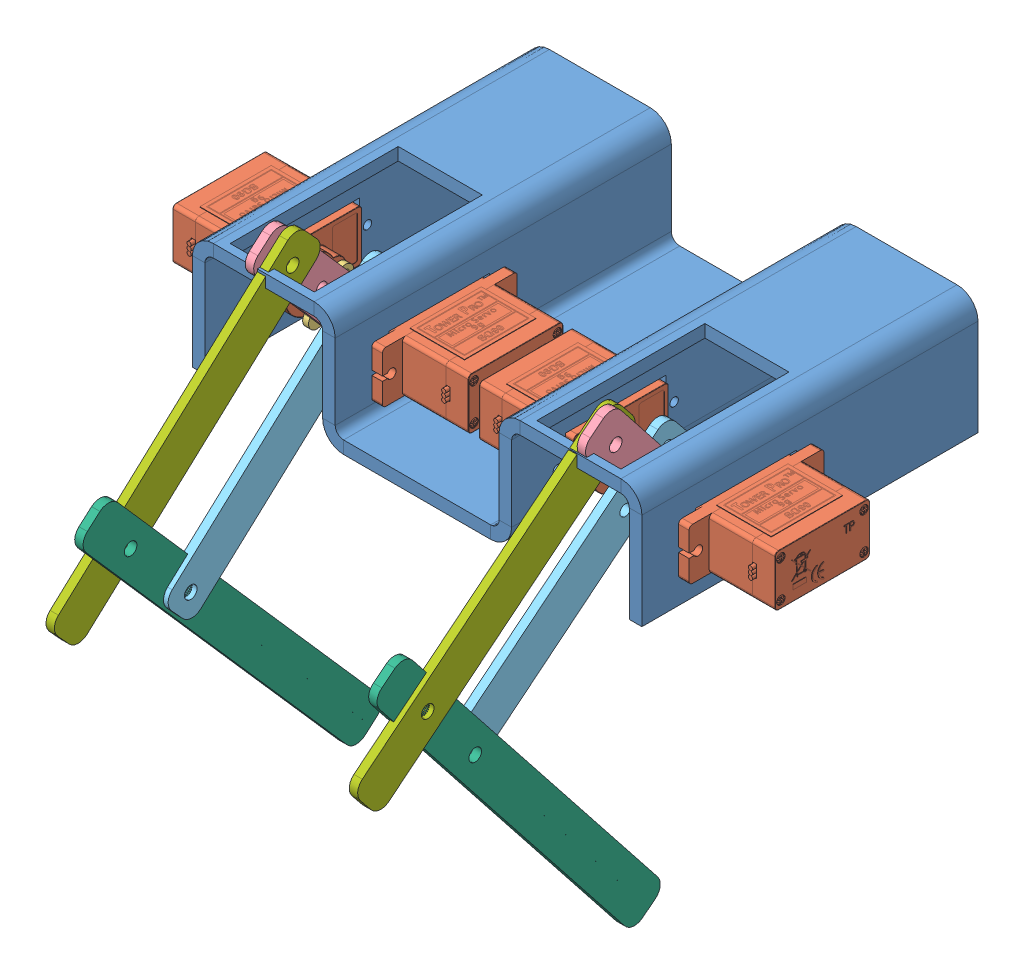
SolidWorks assembly assembly of duck round 2, configuration Default. Lengths in mm.
Overall size (143.6 114.97 133.43).
17 component instances, 7 part files, 41 mates.
Components (placement in the parent):
- body round 2-1: body round 2 [Default] at (-22.1996 -72.5458 50.5255) size (107 28 80)
- SG90 - Micro Servo 9g - Tower Pro.1-1: SG90 - Micro Servo 9g - Tower Pro.1 [Peça] at (-83.3496 -0.75 25.7508) x (0 0 -1) z (0 -1 0) size (32.1 29.95 12.4)
- SG90 - Micro Servo 9g - Tower Pro.1-2: SG90 - Micro Servo 9g - Tower Pro.1 [Peça] at (-34.0496 -0.75 25.7508) x (0 0 -1) z (0 1 0) size (32.1 29.95 12.4)
- SG90 - Micro Servo 9g - Tower Pro.1-3: SG90 - Micro Servo 9g - Tower Pro.1 [Peça] at (-10.3496 -0.75 25.7508) x (0 0 -1) z (0 -1 0) size (32.1 29.95 12.4)
- SG90 - Micro Servo 9g - Tower Pro.1-4: SG90 - Micro Servo 9g - Tower Pro.1 [Peça] at (38.9504 -0.75 25.7508) x (0 0 -1) z (0 1 0) size (32.1 29.95 12.4)
- SG90 - Micro Servo 9g - Tower Pro.4-1: SG90 - Micro Servo 9g - Tower Pro.4 [Peça] at (-55.1496 -0.75 30.9008) x (0 0.737502 0.675345) z (0 -0.675345 0.737502) size (13 3.8 16.7)
- SG90 - Micro Servo 9g - Tower Pro.4-2: SG90 - Micro Servo 9g - Tower Pro.4 [Peça] at (-62.2496 -0.75 30.9008) x (0 0.660205 -0.751086) z (0 -0.751086 -0.660205) size (13 3.8 16.7)
- SG90 - Micro Servo 9g - Tower Pro.4-3: SG90 - Micro Servo 9g - Tower Pro.4 [Peça] at (17.8504 -0.75 30.9008) x (0 -0.620104 0.78452) z (0 -0.78452 -0.620104) size (13 3.8 16.7)
- SG90 - Micro Servo 9g - Tower Pro.4-4: SG90 - Micro Servo 9g - Tower Pro.4 [Peça] at (10.7504 -0.75 30.9008) x (0 0.777148 0.629318) z (0 0.629318 -0.777148) size (13 3.8 16.7)
- arm for servo1-1: arm for servo1 [Default] at (-60.2496 4.6728 35.6674) x (0 -0.751086 -0.660205) z (0 0.660205 -0.751086) size (40 2 10)
- arm for servo2-1: arm for servo2 [Default] at (-57.1496 -17.2378 48.9061) x (0 0.675345 -0.737502) z (0 -0.737502 -0.675345) size (70 2 10)
- arm for servo3-1: arm for servo3 [Default] at (-56.2496 -50.4142 60.4581) x (0 0.751086 0.660205) z (0 -0.660205 0.751086) size (100 2 10)
- arm for servo4-1: arm for servo4 [Default] at (-58.2496 -8.69 69.1799) x (0 0.675345 -0.737502) z (0 0.737502 0.675345) size (80 2 10)
- arm for servo1-2: arm for servo1 [Default] at (15.8504 4.9142 35.3779) x (0 -0.78452 -0.620104) z (0 -0.620104 0.78452) size (40 2 10)
- arm for servo2-3: arm for servo2 [Default] at (10.7504 -16.1141 49.874) x (0 0.629318 -0.777148) z (0 -0.777148 -0.629318) size (70 2 10)
- arm for servo4-2: arm for servo4 [Default] at (13.8504 -6.4564 69.7259) x (0 0.629318 -0.777148) z (0 -0.777148 -0.629318) size (80 2 10)
- arm for servo3-2: arm for servo3 [Default] at (14.7504 -48.44 63.3071) x (0 0.78452 0.620104) z (0 -0.620104 0.78452) size (100 2 10)
Mates (geometry in assembly coordinates):
- Coincident5: coincident: plane of body round 2-1 through (-41.6996 -12.25 -29.4745) normal (1 0 0); plane of SG90 - Micro Servo 9g - Tower Pro.1-2 through (-41.6996 4.5 40.9508) normal (-1 0 0)
- Coincident7: coincident: plane of body round 2-1 through (-2.6996 -12.25 -29.4745) normal (-1 0 0); plane of SG90 - Micro Servo 9g - Tower Pro.1-3 through (-2.6996 -6 40.9508) normal (1 0 0)
- Concentric15: concentric: cylinder of SG90 - Micro Servo 9g - Tower Pro.1-3 through (-20.8996 -0.75 39.6508) axis (1 0 0) radius 1.1; cylinder of body round 2-1 through (31.3004 -0.75 39.6508) axis (-1 0 0) radius 1
- Coincident10: coincident: plane of body round 2-1 through (31.3004 12.75 -29.4745) normal (1 0 0); plane of SG90 - Micro Servo 9g - Tower Pro.1-4 through (31.3004 4.5 40.9508) normal (-1 0 0)
- Concentric17: concentric: cylinder of body round 2-1 through (31.3004 -0.75 39.6508) axis (-1 0 0) radius 1; cylinder of SG90 - Micro Servo 9g - Tower Pro.1-4 through (49.5004 -0.75 39.6508) axis (-1 0 0) radius 1.1
- Coincident13: coincident: plane of SG90 - Micro Servo 9g - Tower Pro.1-2 through (-53.3496 -0.75 30.9008) normal (-1 0 0); plane of SG90 - Micro Servo 9g - Tower Pro.4-1 through (-53.3496 -0.75 30.9008) normal (1 0 0)
- Concentric1: concentric: circle of SG90 - Micro Servo 9g - Tower Pro.1-2; circle of SG90 - Micro Servo 9g - Tower Pro.4-1
- Coincident14: coincident: plane of SG90 - Micro Servo 9g - Tower Pro.1-1 through (-64.0496 -0.75 30.9008) normal (1 0 0); plane of SG90 - Micro Servo 9g - Tower Pro.4-2 through (-64.0496 -0.75 30.9008) normal (-1 0 0)
- Concentric2: concentric: circle of SG90 - Micro Servo 9g - Tower Pro.1-1; circle of SG90 - Micro Servo 9g - Tower Pro.4-2
- Coincident15: coincident: plane of SG90 - Micro Servo 9g - Tower Pro.1-4 through (19.6504 -0.75 30.9008) normal (-1 0 0); plane of SG90 - Micro Servo 9g - Tower Pro.4-3 through (19.6504 -0.75 30.9008) normal (1 0 0)
- Concentric3: concentric: circle of SG90 - Micro Servo 9g - Tower Pro.1-4; circle of SG90 - Micro Servo 9g - Tower Pro.4-3
- Concentric4: concentric: circle of SG90 - Micro Servo 9g - Tower Pro.1-3; circle of SG90 - Micro Servo 9g - Tower Pro.4-4
- Coincident16: coincident: plane of SG90 - Micro Servo 9g - Tower Pro.1-3 through (8.9504 -0.75 30.9008) normal (1 0 0); plane of SG90 - Micro Servo 9g - Tower Pro.4-4 through (8.9504 -0.75 30.9008) normal (-1 0 0)
- Concentric16: concentric: cylinder of SG90 - Micro Servo 9g - Tower Pro.1-3 through (-20.8996 -0.75 11.8508) axis (1 0 0) radius 1.1; cylinder of body round 2-1 through (31.3004 -0.75 11.8508) axis (-1 0 0) radius 1
- Concentric18: concentric: cylinder of body round 2-1 through (31.3004 -0.75 11.8508) axis (-1 0 0) radius 1; cylinder of SG90 - Micro Servo 9g - Tower Pro.1-4 through (49.5004 -0.75 11.8508) axis (-1 0 0) radius 1.1
- Concentric19: concentric: cylinder of SG90 - Micro Servo 9g - Tower Pro.4-2 through (-62.2496 4.0945 35.1591) axis (1 0 0) radius 1.25; cylinder of arm for servo1-1 through (-59.2496 4.0945 35.1591) axis (-1 0 0) radius 1.3
- Concentric20: concentric: cylinder of SG90 - Micro Servo 9g - Tower Pro.4-2 through (-62.2496 -5.5945 26.6424) axis (1 0 0) radius 1.25; cylinder of arm for servo1-1 through (-59.2496 -5.5945 26.6424) axis (-1 0 0) radius 1.3
- Coincident19: coincident: plane of SG90 - Micro Servo 9g - Tower Pro.4-2 through (-62.2496 -0.75 30.9008) normal (1 0 0); plane of arm for servo1-1 through (-62.2496 4.6728 35.6674) normal (-1 0 0)
- Concentric21: concentric: cylinder of SG90 - Micro Servo 9g - Tower Pro.4-1 through (-55.1496 3.606 26.1439) axis (-1 0 0) radius 1.25; cylinder of arm for servo2-1 through (-58.1496 3.606 26.1439) axis (1 0 0) radius 1.3
- Concentric22: concentric: cylinder of arm for servo2-1 through (-58.1496 -5.106 35.6577) axis (1 0 0) radius 1.3; cylinder of SG90 - Micro Servo 9g - Tower Pro.4-1 through (-55.1496 -5.106 35.6577) axis (-1 0 0) radius 1.25
- Coincident20: coincident: plane of SG90 - Micro Servo 9g - Tower Pro.4-1 through (-55.1496 -0.75 30.9008) normal (-1 0 0); plane of arm for servo2-1 through (-55.1496 -17.2378 48.9061) normal (1 0 0)
- Concentric23: concentric: cylinder of arm for servo2-1 through (-55.1496 -37.894 71.4634) axis (1 0 0) radius 1.5; cylinder of arm for servo3-1 through (-58.2496 -37.894 71.4634) axis (-1 0 0) radius 1.5
- Concentric24: concentric: cylinder of arm for servo1-1 through (-62.2496 14.2717 44.1049) axis (-1 0 0) radius 1.5; cylinder of arm for servo4-1 through (-58.2496 14.2717 44.1049) axis (1 0 0) radius 1.5
- Concentric25: concentric: cylinder of arm for servo3-1 through (-58.2496 -22.8723 84.6675) axis (-1 0 0) radius 1.5; cylinder of arm for servo4-1 through (-58.2496 -22.8723 84.6675) axis (1 0 0) radius 1.5
- Coincident21: coincident: plane of arm for servo1-1 through (-60.2496 4.6728 35.6674) normal (1 0 0); plane of arm for servo4-1 through (-60.2496 -8.69 69.1799) normal (-1 0 0)
- Coincident22: coincident: plane of arm for servo3-1 through (-58.2496 -50.4142 60.4581) normal (-1 0 0); plane of arm for servo4-1 through (-58.2496 -8.69 69.1799) normal (1 0 0)
- Parallel1: parallel: plane of arm for servo2-1 through (-57.1496 -17.2378 48.9061) normal (-1 0 0); plane of arm for servo3-1 through (-56.2496 -50.4142 60.4581) normal (1 0 0)
- Concentric30: concentric: circle of SG90 - Micro Servo 9g - Tower Pro.4-4; circle of arm for servo2-3
- Concentric31: concentric: circle of SG90 - Micro Servo 9g - Tower Pro.4-4; circle of arm for servo2-3
- Concentric32: concentric: circle of SG90 - Micro Servo 9g - Tower Pro.4-3; circle of arm for servo1-2
- Concentric33: concentric: circle of SG90 - Micro Servo 9g - Tower Pro.4-3; circle of arm for servo1-2
- Coincident26: coincident: plane of SG90 - Micro Servo 9g - Tower Pro.4-3 through (17.8504 -0.75 30.9008) normal (-1 0 0); plane of arm for servo1-2 through (17.8504 4.9142 35.3779) normal (1 0 0)
- Coincident27: coincident: plane of SG90 - Micro Servo 9g - Tower Pro.4-4 through (10.7504 -0.75 30.9008) normal (1 0 0); plane of arm for servo2-3 through (10.7504 -16.1141 49.874) normal (-1 0 0)
- Coincident29: coincident: circle of arm for servo1-2; circle of arm for servo4-2
- Coincident30: coincident: circle of arm for servo2-3; circle of arm for servo3-2
- Concentric34: concentric: cylinder of arm for servo4-2 through (13.8504 -19.6721 86.046) axis (-1 0 0) radius 1.5; cylinder of arm for servo3-2 through (12.7504 -19.6721 86.046) axis (-1 0 0) radius 1.5
- Concentric35: concentric: circle of body round 2-1; circle of SG90 - Micro Servo 9g - Tower Pro.1-1
- Coincident33: coincident: plane of body round 2-1 through (-75.6996 12.75 -29.4745) normal (-1 0 0); plane of SG90 - Micro Servo 9g - Tower Pro.1-1 through (-75.6996 -6 40.9508) normal (1 0 0)
- Concentric36: concentric: cylinder of body round 2-1 through (31.3004 -0.75 11.8508) axis (-1 0 0) radius 1; cylinder of SG90 - Micro Servo 9g - Tower Pro.1-1 through (-93.8996 -0.75 11.8508) axis (1 0 0) radius 1.1
- Concentric37: concentric: circle of body round 2-1; circle of SG90 - Micro Servo 9g - Tower Pro.1-2
- Concentric38: concentric: circle of body round 2-1; circle of SG90 - Micro Servo 9g - Tower Pro.1-2
